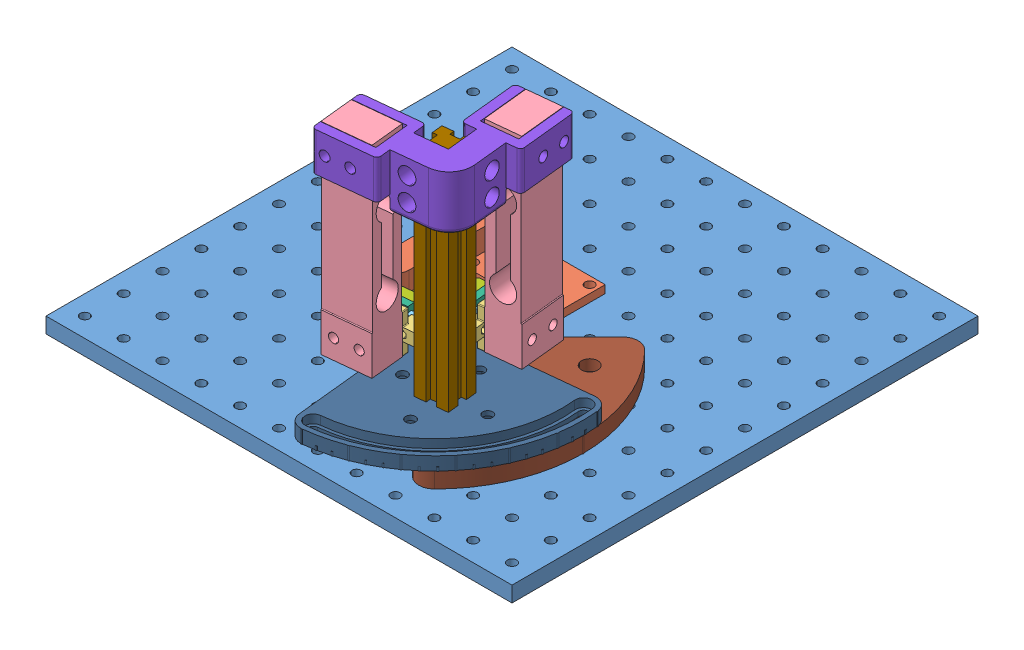
SolidWorks assembly ASM3_v2, configuration 기본. Lengths in mm.
Overall size (300 175.5 300.09).
15 component instances, 11 part files, 49 mates.
Components (placement in the parent):
- platform-1: platform [기본] at (-708.9249 -138.0932 300) size (300 10 300)
- finger_model-1: finger_model [기본] at (-721.4249 -128.0932 287.5) size (60 55 113.75)
- linear_guide_holder_vertical_axis-1: linear_guide_holder_vertical_axis [기본] at (-663.8961 -80.0932 349.4713) x (0 1 0) z (-0.994671 0 0.103102) size (25 45 15)
- Loadcell-1: Loadcell [기본] at (-654.5012 -27.5932 333.4171) x (0 1 0) z (0.103102 0 0.994671) size (130 22 30)
- linear_guide_holder_vertical_axis-2: linear_guide_holder_vertical_axis [기본] at (-700.8962 -80.0932 395.0288) x (0 -1 0) z (-0.103102 0 -0.994671) size (25 45 15)
- Loadcell-2: Loadcell [기본] at (-684.842 -27.5932 404.4237) x (0 1 0) z (-0.994671 0 0.103102) size (130 22 30)
- linear_guide_part1-1: linear_guide_part1 [기본] at (-702.3912 -80.0932 380.6061) x (0.994671 0 -0.103102) z (0 -1 0) size (40 4 5)
- linear_guide_part2-1: linear_guide_part2 [기본] at (-702.1231 -80.0932 383.1923) x (-0.994671 0 0.103102) z (0 -1 0) size (17 4.6 12)
- linear_guide_part1-2: linear_guide_part1 [기본] at (-674.3401 -80.0932 350.5538) x (-0.103102 0 -0.994671) z (0 1 0) size (40 4 5)
- linear_guide_part2-2: linear_guide_part2 [기본] at (-675.7327 -80.0932 350.6982) x (0.103102 0 0.994671) z (0 -1 0) size (17 4.6 12)
- contact_part_vertical-1: contact_part_vertical [기본] at (-705.1749 -80.0932 353.75) x (-0.103102 0 -0.994671) z (0 1 0) size (33.5 33.5 13)
- Loadcell_holder_vertical_part1-1: Loadcell_holder_vertical_part1 [기본] at (-647.5418 12.4068 400.5574) x (0.994671 0 -0.103102) z (0.103102 0 0.994671) size (85 35 85)
- profile_20x20x140-1: profile_20x20x140 [기본] at (-668.1251 -109.5932 383.8404) x (0.994671 0 -0.103102) z (0.103102 0 0.994671) size (20 140 20)
- rotary_guide_part1_v2-1: rotary_guide_part1_v2 [기본] at (-705.1749 -118.0932 353.75) x (0.994671 0 -0.103102) z (0.103102 0 0.994671) size (104.25 8.5 104.25)
- rotary_guide_part2_v2-1: rotary_guide_part2_v2 [기본] at (-705.1749 -128.0932 353.75) x (0 0 -1) z (1 0 0) size (141.27 10 106)
Mates (geometry in assembly coordinates):
- 동심1: concentric aligned: cylinder of platform-1 through (-696.4249 -128.0932 287.5) axis (0 -1 0) radius 3; cylinder of finger_model-1 through (-696.4249 -123.0932 287.5) axis (0 -1 0) radius 3
- 동심2: concentric aligned: cylinder of platform-1 through (-746.4249 -128.0932 287.5) axis (0 -1 0) radius 3; cylinder of finger_model-1 through (-746.4249 -123.0932 287.5) axis (0 -1 0) radius 3
- 일치1: coincident anti-aligned: plane of platform-1 through (-708.9249 -128.0932 300) normal (0 1 0); plane of finger_model-1 through (-721.4249 -128.0932 287.5) normal (0 -1 0)
- 일치2: coincident anti-aligned: plane of linear_guide_holder_vertical_axis-1 through (-663.8961 -80.0932 349.4713) normal (0.994671 0 -0.103102); plane of Loadcell-1 through (-662.3496 -92.5932 364.3913) normal (-0.994671 0 0.103102)
- 동심3: concentric anti-aligned: cylinder of linear_guide_holder_vertical_axis-1 through (-668.648 -80.0932 342.4236) axis (0.994671 0 -0.103102) radius 3.2; cylinder of Loadcell-1 through (-634.3465 -80.0932 338.8681) axis (-0.994671 0 0.103102) radius 3
- 동심4: concentric anti-aligned: cylinder of linear_guide_holder_vertical_axis-1 through (-667.1015 -80.0932 357.3437) axis (0.994671 0 -0.103102) radius 3.2; cylinder of Loadcell-1 through (-632.8 -80.0932 353.7882) axis (-0.994671 0 0.103102) radius 3
- 평행2: parallel anti-aligned: plane of platform-1 through (-708.9249 -128.0932 300) normal (0 1 0); plane of Loadcell-1 through (-662.3496 -92.5932 364.3913) normal (0 -1 0)
- 평행3: parallel anti-aligned: plane of platform-1 through (-708.9249 -128.0932 300) normal (0 1 0); plane of Loadcell-2 through (-715.8162 -92.5932 396.5754) normal (0 -1 0)
- 동심5: concentric anti-aligned: cylinder of linear_guide_holder_vertical_axis-2 through (-708.7686 -80.0932 391.8234) axis (0.103102 0 0.994671) radius 3.2; cylinder of Loadcell-2 through (-705.2131 -80.0932 426.1249) axis (-0.103102 0 -0.994671) radius 3
- 동심6: concentric anti-aligned: cylinder of linear_guide_holder_vertical_axis-2 through (-693.8486 -80.0932 390.2769) axis (0.103102 0 0.994671) radius 3.2; cylinder of Loadcell-2 through (-690.2931 -80.0932 424.5784) axis (-0.103102 0 -0.994671) radius 3
- 일치7: coincident anti-aligned: plane of linear_guide_holder_vertical_axis-2 through (-700.8962 -80.0932 395.0288) normal (0.103102 0 0.994671); plane of Loadcell-2 through (-715.8162 -92.5932 396.5754) normal (-0.103102 0 -0.994671)
- 동심7: concentric anti-aligned: cylinder of linear_guide_holder_vertical_axis-2 through (-687.0587 -80.0932 383.0383) axis (0.103102 0 0.994671) radius 1.15; cylinder of linear_guide_part1-1 through (-687.0587 -80.0932 383.0383) axis (-0.103102 0 -0.994671) radius 1.25
- 동심8: concentric anti-aligned: cylinder of linear_guide_holder_vertical_axis-2 through (-716.8988 -80.0932 386.1313) axis (0.103102 0 0.994671) radius 1.15; cylinder of linear_guide_part1-1 through (-716.8988 -80.0932 386.1313) axis (-0.103102 0 -0.994671) radius 1.25
- 일치8: coincident anti-aligned: plane of linear_guide_holder_vertical_axis-2 through (-701.9788 -80.0932 384.5848) normal (-0.103102 0 -0.994671); plane of linear_guide_part1-1 through (-701.9788 -80.0932 384.5848) normal (0.103102 0 0.994671)
- 너비1: width anti-aligned: plane of linear_guide_part2-1 through (-708.7508 -77.5932 401.6942) normal (0 -1 0); plane of linear_guide_part2-1 through (-708.7508 -82.5932 401.6942) normal (0 1 0); plane of linear_guide_part1-1 through (-682.0853 -77.5932 382.5228) normal (0 1 0); plane of linear_guide_part1-1 through (-682.0853 -82.5932 382.5228) normal (0 -1 0)
- 일치9: coincident anti-aligned: plane of linear_guide_part1-1 through (-702.3912 -80.0932 380.6061) normal (-0.103102 0 -0.994671); plane of linear_guide_part2-1 through (-702.3912 -80.0932 380.6061) normal (0.103102 0 0.994671)
- 거리 한도1: limit distance = 11.7 mm anti-aligned: plane of linear_guide_part2-1 through (-711.0521 -74.0932 379.4931) normal (-0.994671 0 0.103102); plane of linear_guide_holder_vertical_axis-2 through (-722.5351 -76.0932 382.1914) normal (0.994671 0 -0.103102)
- 거리 한도2: limit distance = 11.7 mm anti-aligned: plane of linear_guide_holder_vertical_axis-2 through (-682.3504 -76.0932 378.0261) normal (-0.994671 0 0.103102); plane of linear_guide_part2-1 through (-694.1427 -74.0932 377.7404) normal (0.994671 0 -0.103102)
- 일치11: coincident anti-aligned: plane of linear_guide_holder_vertical_axis-1 through (-674.3401 -80.0932 350.5538) normal (-0.994671 0 0.103102); plane of linear_guide_part1-2 through (-674.3401 -80.0932 350.5538) normal (0.994671 0 -0.103102)
- 동심9: concentric aligned: cylinder of linear_guide_holder_vertical_axis-1 through (-672.7936 -80.0932 365.4739) axis (0.994671 0 -0.103102) radius 1.15; cylinder of linear_guide_part1-2 through (-676.7723 -80.0932 365.8863) axis (0.994671 0 -0.103102) radius 1.25
- 동심10: concentric aligned: cylinder of linear_guide_holder_vertical_axis-1 through (-675.8867 -80.0932 335.6338) axis (0.994671 0 -0.103102) radius 1.15; cylinder of linear_guide_part1-2 through (-679.8653 -80.0932 336.0462) axis (0.994671 0 -0.103102) radius 1.25
- 일치12: coincident anti-aligned: plane of linear_guide_part1-2 through (-678.3188 -80.0932 350.9662) normal (-0.994671 0 0.103102); plane of linear_guide_part2-2 through (-678.3188 -80.0932 350.9662) normal (0.994671 0 -0.103102)
- 거리 한도3: limit distance = 11.7 mm anti-aligned: plane of linear_guide_holder_vertical_axis-1 through (-676.7335 -84.0932 371.1101) normal (-0.103102 0 -0.994671); plane of linear_guide_part2-2 through (-679.4318 -74.0932 359.6271) normal (0.103102 0 0.994671)
- 거리 한도4: limit distance = 11.7 mm anti-aligned: plane of linear_guide_holder_vertical_axis-1 through (-680.8988 -84.0932 330.9254) normal (0.103102 0 0.994671); plane of linear_guide_part2-2 through (-681.1845 -74.0932 342.7177) normal (-0.103102 0 -0.994671)
- 일치13: coincident anti-aligned: plane of linear_guide_part2-2 through (-680.3082 -80.0932 351.1724) normal (-0.994671 0 0.103102); plane of contact_part_vertical-1 through (-680.3082 -80.0932 351.1724) normal (0.994671 0 -0.103102)
- 동심11: concentric anti-aligned: cylinder of linear_guide_part2-2 through (-678.3188 -84.0932 350.9662) axis (-0.994671 0 0.103102) radius 1; cylinder of contact_part_vertical-1 through (-686.5746 -84.0932 351.822) axis (0.994671 0 -0.103102) radius 1.15
- 동심12: concentric anti-aligned: cylinder of linear_guide_part2-2 through (-678.3188 -76.0932 350.9662) axis (-0.994671 0 0.103102) radius 1; cylinder of contact_part_vertical-1 through (-686.5746 -76.0932 351.822) axis (0.994671 0 -0.103102) radius 1.15
- 동심13: concentric anti-aligned: cylinder of linear_guide_part2-1 through (-702.3912 -76.0932 380.6061) axis (-0.103102 0 -0.994671) radius 1; cylinder of contact_part_vertical-1 through (-703.2469 -76.0932 372.3503) axis (0.103102 0 0.994671) radius 1.15
- 동심14: concentric anti-aligned: cylinder of linear_guide_part2-1 through (-702.3912 -84.0932 380.6061) axis (-0.103102 0 -0.994671) radius 1; cylinder of contact_part_vertical-1 through (-703.2469 -84.0932 372.3503) axis (0.103102 0 0.994671) radius 1.15
- 일치14: coincident anti-aligned: plane of linear_guide_part2-1 through (-702.5974 -80.0932 378.6168) normal (-0.103102 0 -0.994671); plane of contact_part_vertical-1 through (-702.5974 -80.0932 378.6168) normal (0.103102 0 0.994671)
- 너비5: width anti-aligned: plane of Loadcell_holder_vertical_part1-1 through (-640.2181 37.4068 362.0973) normal (-0.994671 0 0.103102); plane of Loadcell_holder_vertical_part1-1 through (-665.6913 37.4068 334.577) normal (0.994671 0 -0.103102); plane of Loadcell-1 through (-640.4668 12.4068 362.1231) normal (0.994671 0 -0.103102); plane of Loadcell-1 through (-662.3496 12.4068 364.3913) normal (-0.994671 0 0.103102)
- 동심15: concentric anti-aligned: cylinder of Loadcell-1 through (-634.3465 24.9068 338.8681) axis (-0.994671 0 0.103102) radius 3; cylinder of Loadcell_holder_vertical_part1-1 through (-680.1374 24.9068 343.6146) axis (0.994671 0 -0.103102) radius 3.2
- 동심16: concentric anti-aligned: cylinder of Loadcell-1 through (-632.8 24.9068 353.7882) axis (-0.994671 0 0.103102) radius 3; cylinder of Loadcell_holder_vertical_part1-1 through (-678.5909 24.9068 358.5346) axis (0.994671 0 -0.103102) radius 3.2
- 너비6: width aligned: plane of Loadcell-2 through (-713.548 12.4068 418.4581) normal (0.103102 0 0.994671); plane of Loadcell-2 through (-715.8162 12.4068 396.5754) normal (-0.103102 0 -0.994671); plane of Loadcell_holder_vertical_part1-1 through (-686.0019 37.4068 393.2336) normal (0.103102 0 0.994671); plane of Loadcell_holder_vertical_part1-1 through (-713.5222 37.4068 418.7068) normal (-0.103102 0 -0.994671)
- 동심17: concentric anti-aligned: cylinder of Loadcell-2 through (-690.2931 24.9068 424.5784) axis (-0.103102 0 -0.994671) radius 3; cylinder of Loadcell_holder_vertical_part1-1 through (-695.0395 24.9068 378.7875) axis (0.103102 0 0.994671) radius 3.2
- 동심18: concentric anti-aligned: cylinder of Loadcell-2 through (-705.2131 24.9068 426.1249) axis (-0.103102 0 -0.994671) radius 3; cylinder of Loadcell_holder_vertical_part1-1 through (-709.9596 24.9068 380.334) axis (0.103102 0 0.994671) radius 3.2
- 너비7: width aligned: plane of finger_model-1 through (-721.4249 -73.0932 287.5) normal (0 1 0); plane of finger_model-1 through (-721.4249 -87.0932 287.5) normal (0 -1 0); plane of contact_part_vertical-1 through (-687.4509 -74.0932 343.3673) normal (0 1 0); plane of contact_part_vertical-1 through (-687.4509 -86.0932 343.3673) normal (0 -1 0)
- 너비10: width anti-aligned: plane of Loadcell_holder_vertical_part1-1 through (-659.0311 -53.2834 372.6432) normal (0.103102 0 0.994671); plane of Loadcell_holder_vertical_part1-1 through (-656.9278 -53.2834 392.9344) normal (-0.103102 0 -0.994671); plane of profile_20x20x140-1 through (-666.1721 30.4068 373.5844) normal (-0.103102 0 -0.994671); plane of profile_20x20x140-1 through (-664.1101 30.4068 393.4778) normal (0.103102 0 0.994671)
- 일치19: coincident anti-aligned: plane of profile_20x20x140-1 through (-668.1251 -109.5932 383.8404) normal (0 -1 0); plane of rotary_guide_part1_v2-1 through (-682.7948 -109.5932 351.4302) normal (0 1 0)
- 너비11: width aligned: plane of profile_20x20x140-1 through (-659.2094 30.4068 372.8627) normal (0.994671 0 -0.103102); plane of profile_20x20x140-1 through (-679.1028 30.4068 374.9248) normal (-0.994671 0 0.103102); plane of Loadcell_holder_vertical_part1-1 through (-677.2191 -53.2834 395.0377) normal (0.994671 0 -0.103102); plane of Loadcell_holder_vertical_part1-1 through (-656.9278 -53.2834 392.9344) normal (-0.994671 0 0.103102)
- 너비12: width: plane of profile_20x20x140-1 through (-658.4877 30.4068 379.8254) normal (0.103102 0 0.994671); plane of profile_20x20x140-1 through (-657.8691 30.4068 385.7934) normal (-0.103102 0 -0.994671); cylinder of rotary_guide_part1_v2-1 through (-643.2583 -109.5932 381.2629) axis (0 -1 0) radius 3.2
- 너비13: width: plane of profile_20x20x140-1 through (-670.0781 30.4068 394.0965) normal (0.994671 0 -0.103102); plane of profile_20x20x140-1 through (-664.1101 30.4068 393.4778) normal (-0.994671 0 0.103102); cylinder of rotary_guide_part1_v2-1 through (-665.5475 -109.5932 408.7072) axis (0 -1 0) radius 3.2
- 너비15: width: plane of profile_20x20x140-1 through (-678.3811 30.4068 381.8874) normal (0.103102 0 0.994671); plane of profile_20x20x140-1 through (-677.7625 30.4068 387.8555) normal (-0.103102 0 -0.994671); cylinder of rotary_guide_part1_v2-1 through (-692.9919 -109.5932 386.418) axis (0 -1 0) radius 3.2
- 탄젠트6: tangent aligned: cylinder of rotary_guide_part1_v2-1 through (-705.1749 -109.5932 353.75) axis (0 -1 0) radius 90.75; cylinder of rotary_guide_part2_v2-1 through (-617.6749 -137.2856 353.75) axis (0 1 0) radius 3.25
- 동심43: concentric aligned: cylinder of rotary_guide_part1_v2-1 through (-705.1749 -127.2856 353.75) axis (0 1 0) radius 3.25; cylinder of rotary_guide_part2_v2-1 through (-705.1749 -137.2856 353.75) axis (0 1 0) radius 3.25
- 일치25: coincident anti-aligned: plane of platform-1 through (-708.9249 -128.0932 300) normal (0 1 0); plane of rotary_guide_part2_v2-1 through (-705.1749 -128.0932 353.75) normal (0 -1 0)
- 동심44: concentric aligned: cylinder of platform-1 through (-696.4249 -128.0932 362.5) axis (0 -1 0) radius 3; cylinder of rotary_guide_part2_v2-1 through (-696.4249 -118.0932 362.5) axis (0 -1 0) radius 3.2
- 동심45: concentric aligned: cylinder of platform-1 through (-646.4249 -128.0932 362.5) axis (0 -1 0) radius 3; cylinder of rotary_guide_part2_v2-1 through (-646.4249 -118.0932 362.5) axis (0 -1 0) radius 3.2
- 일치26: coincident anti-aligned: plane of rotary_guide_part1_v2-1 through (-682.7948 -118.0932 351.4302) normal (0 -1 0); plane of rotary_guide_part2_v2-1 through (-705.1749 -118.0932 353.75) normal (0 1 0)
